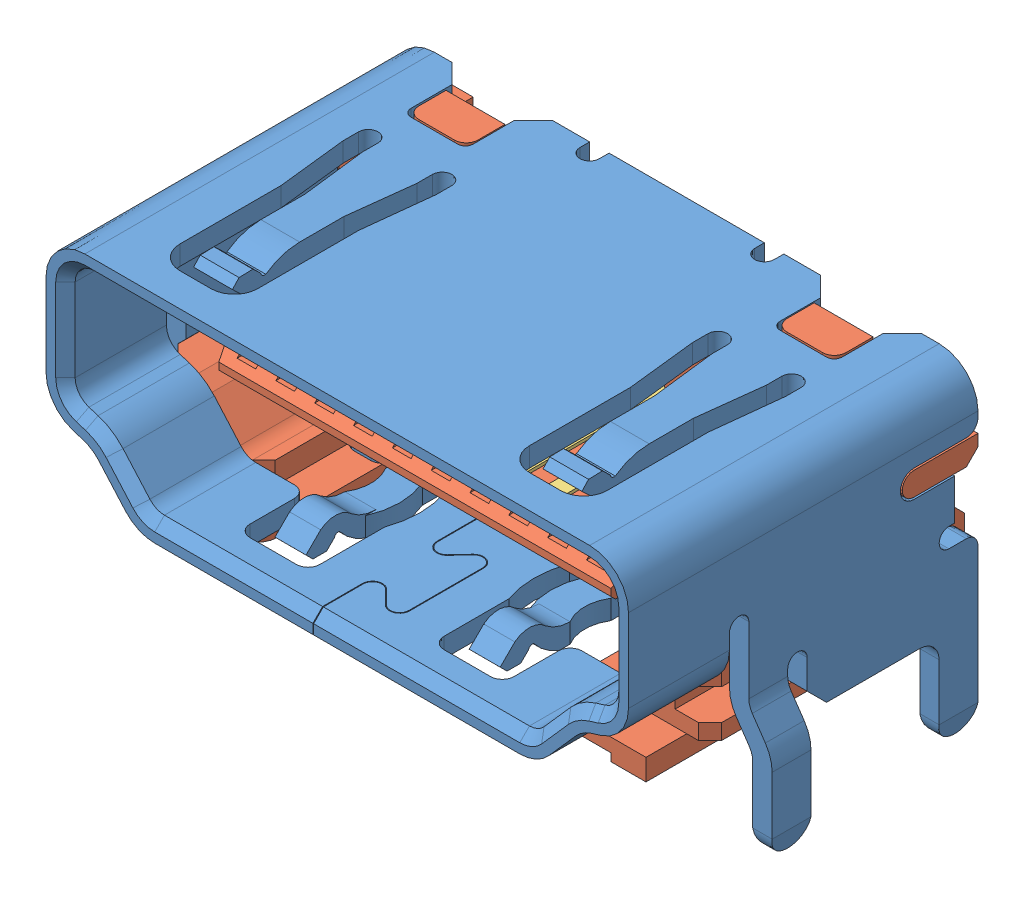
SolidWorks assembly HDMI-Buchse, configuration Default. Lengths in mm.
Overall size (16.2 8 9.9).
21 component instances, 4 part files, 0 mates.
Components (placement in the parent):
- HDMI-Outer-1: HDMI-Outer [Default] at (-20 0 0) size (16.2 8 9)
- HDMI-Inner-1: HDMI-Inner [Default] at (-20 0 0) size (15 6.1 7.6)
- HDMI-Contact-1: HDMI-Contact [Valor predeterminado] at (-201.7661 0.45 76.5103) x (0 0 -1) z (0 -1 0) size (7.55 0.65 3.84)
- HDMI-Contact-Lower-1: HDMI-Contact-Lower [Valor predeterminado] at (-202.2661 -0.25 76.5103) x (0 0 -1) z (0 -1 0) size (7.55 0.65 3.08)
- HDMI-Contact-2: HDMI-Contact [Valor predeterminado] at (-202.7661 0.45 76.5103) x (0 0 -1) z (0 -1 0) size (7.55 0.65 3.84)
- HDMI-Contact-3: HDMI-Contact [Valor predeterminado] at (-203.7661 0.45 76.5103) x (0 0 -1) z (0 -1 0) size (7.55 0.65 3.84)
- HDMI-Contact-4: HDMI-Contact [Valor predeterminado] at (-204.7661 0.45 76.5103) x (0 0 -1) z (0 -1 0) size (7.55 0.65 3.84)
- HDMI-Contact-5: HDMI-Contact [Valor predeterminado] at (-205.7661 0.45 76.5103) x (0 0 -1) z (0 -1 0) size (7.55 0.65 3.84)
- HDMI-Contact-6: HDMI-Contact [Valor predeterminado] at (-206.7661 0.45 76.5103) x (0 0 -1) z (0 -1 0) size (7.55 0.65 3.84)
- HDMI-Contact-7: HDMI-Contact [Valor predeterminado] at (-207.7661 0.45 76.5103) x (0 0 -1) z (0 -1 0) size (7.55 0.65 3.84)
- HDMI-Contact-8: HDMI-Contact [Valor predeterminado] at (-208.7661 0.45 76.5103) x (0 0 -1) z (0 -1 0) size (7.55 0.65 3.84)
- HDMI-Contact-9: HDMI-Contact [Valor predeterminado] at (-209.7661 0.45 76.5103) x (0 0 -1) z (0 -1 0) size (7.55 0.65 3.84)
- HDMI-Contact-10: HDMI-Contact [Valor predeterminado] at (-210.7661 0.45 76.5103) x (0 0 -1) z (0 -1 0) size (7.55 0.65 3.84)
- HDMI-Contact-Lower-2: HDMI-Contact-Lower [Valor predeterminado] at (-203.2661 -0.25 76.5103) x (0 0 -1) z (0 -1 0) size (7.55 0.65 3.08)
- HDMI-Contact-Lower-3: HDMI-Contact-Lower [Valor predeterminado] at (-204.2661 -0.25 76.5103) x (0 0 -1) z (0 -1 0) size (7.55 0.65 3.08)
- HDMI-Contact-Lower-4: HDMI-Contact-Lower [Valor predeterminado] at (-205.2661 -0.25 76.5103) x (0 0 -1) z (0 -1 0) size (7.55 0.65 3.08)
- HDMI-Contact-Lower-5: HDMI-Contact-Lower [Valor predeterminado] at (-206.2661 -0.25 76.5103) x (0 0 -1) z (0 -1 0) size (7.55 0.65 3.08)
- HDMI-Contact-Lower-6: HDMI-Contact-Lower [Valor predeterminado] at (-207.2661 -0.25 76.5103) x (0 0 -1) z (0 -1 0) size (7.55 0.65 3.08)
- HDMI-Contact-Lower-7: HDMI-Contact-Lower [Valor predeterminado] at (-208.2661 -0.25 76.5103) x (0 0 -1) z (0 -1 0) size (7.55 0.65 3.08)
- HDMI-Contact-Lower-8: HDMI-Contact-Lower [Valor predeterminado] at (-209.2661 -0.25 76.5103) x (0 0 -1) z (0 -1 0) size (7.55 0.65 3.08)
- HDMI-Contact-Lower-9: HDMI-Contact-Lower [Valor predeterminado] at (-210.2661 -0.25 76.5103) x (0 0 -1) z (0 -1 0) size (7.55 0.65 3.08)
